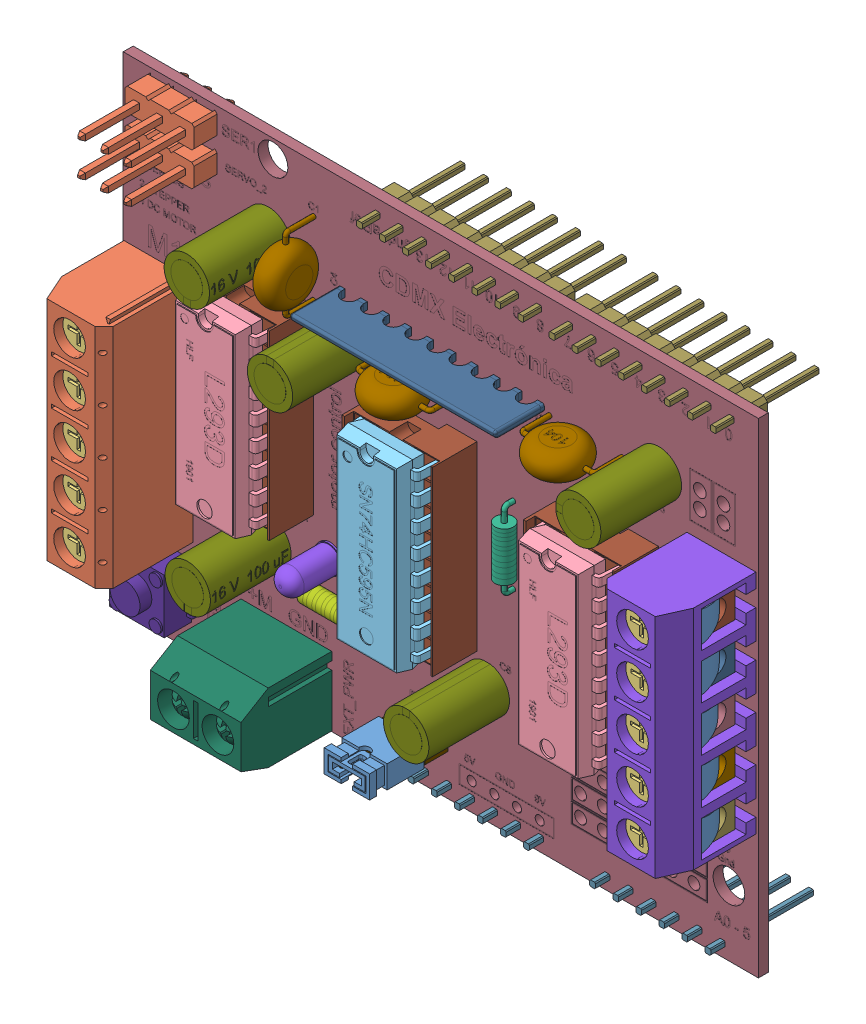
SolidWorks assembly shield-l293d, configuration Default. Lengths in mm.
Overall size (70 53.4 19.79).
64 component instances, 31 part files, 0 mates.
Components (placement in the parent):
- shield-l293d.step-1: shield-l293d.step [Default] at origin size (70 53.4 19.79)
  - bornera 5 pines.step-1: bornera 5 pines.step [Default] at (-31.0088 -3.6709 1.2) x (0 -1 0) z (0 0 1) size (25.5 7.6 12)
    - parte de la bornera_modulo_shield.step-1: parte de la bornera_modulo_shield.step [Default] at (-10 -3.5 5) size (3.8 1.71 4.12)
    - parte de la bornera_modulo_shield.step-2: parte de la bornera_modulo_shield.step [Default] at (-5.0316 -3.4204 4.9792) size (3.8 1.71 4.12)
    - parte de la bornera_modulo_shield.step-3: parte de la bornera_modulo_shield.step [Default] at (-0.05 -3.4087 5.0853) size (3.8 1.71 4.12)
    - parte de la bornera_modulo_shield.step-4: parte de la bornera_modulo_shield.step [Default] at (5.1 -3.4627 4.9734) size (3.8 1.71 4.12)
    - parte de la bornera_modulo_shield.step-5: parte de la bornera_modulo_shield.step [Default] at (10 -3.5442 5.0595) size (3.8 1.71 4.12)
    - bornera 5 pines-0.step-1: bornera 5 pines-0.step [Default] at origin size (25.5 7.6 9.8)
    - bornera 5 pines-1.step-1: bornera 5 pines-1.step [Default] at origin size (3.8 6 8)
    - bornera 5 pines-2.step-1: bornera 5 pines-2.step [Default] at origin size (3.8 6 8)
    - bornera 5 pines-3.step-1: bornera 5 pines-3.step [Default] at origin size (3.8 6 8)
    - bornera 5 pines-4.step-1: bornera 5 pines-4.step [Default] at origin size (3.8 6 8)
    - bornera 5 pines-5.step-1: bornera 5 pines-5.step [Default] at origin size (3.8 6 8)
  - bornera 5 pines_1.step-1: bornera 5 pines_1.step [Default] at (31.0291 -0.4912 1.2) x (0 1 0) z (0 0 1) size (25.5 7.6 12)
    - parte de la bornera_modulo_shield.step-1: parte de la bornera_modulo_shield.step [Default] at (-10 -3.5 5) size (3.8 1.71 4.12)
    - parte de la bornera_modulo_shield.step-2: parte de la bornera_modulo_shield.step [Default] at (-5.0316 -3.4204 4.9792) size (3.8 1.71 4.12)
    - parte de la bornera_modulo_shield.step-3: parte de la bornera_modulo_shield.step [Default] at (-0.05 -3.4087 5.0853) size (3.8 1.71 4.12)
    - parte de la bornera_modulo_shield.step-4: parte de la bornera_modulo_shield.step [Default] at (5.1 -3.4627 4.9734) size (3.8 1.71 4.12)
    - parte de la bornera_modulo_shield.step-5: parte de la bornera_modulo_shield.step [Default] at (10 -3.5442 5.0595) size (3.8 1.71 4.12)
    - bornera 5 pines_1-6.step-1: bornera 5 pines_1-6.step [Default] at origin size (25.5 7.6 9.8)
    - bornera 5 pines_1-7.step-1: bornera 5 pines_1-7.step [Default] at origin size (3.8 6 8)
    - bornera 5 pines_1-8.step-1: bornera 5 pines_1-8.step [Default] at origin size (3.8 6 8)
    - bornera 5 pines_1-9.step-1: bornera 5 pines_1-9.step [Default] at origin size (3.8 6 8)
    - bornera 5 pines_1-10.step-1: bornera 5 pines_1-10.step [Default] at origin size (3.8 6 8)
    - bornera 5 pines_1-11.step-1: bornera 5 pines_1-11.step [Default] at origin size (3.8 6 8)
  - header_macho_6pines.step-1: header_macho_6pines.step [Default] at (31 -25.33 -0.33) x (0 1 0) z (-1 0 0) size (2.54 11.34 15.24)
  - header_macho_6pines.step-2: header_macho_6pines.step [Default] at (11 -25.33 -0.33) x (0 1 0) z (-1 0 0) size (2.54 11.34 15.24)
  - bornera.step-1: bornera.step [Default] at (-17 -22.8156 1.1155) x (1 0 0) z (0 -1 0) size (10.5 13.75 7.6)
  - capacitor 16 v 100uf.step-1: capacitor 16 v 100uf.step [Default] at (-19 -12 1) size (5.01 4.97 12)
  - capacitor 16 v 100uf.step-2: capacitor 16 v 100uf.step [Default] at (-19 17.4 1.1) size (5.01 4.97 12)
  - capacitor 16 v 100uf.step-3: capacitor 16 v 100uf.step [Default] at (5.0692 -13.9959 1) x (-1 0 0) z (0 0 1) size (5.01 4.97 12)
  - capacitor 16 v 100uf.step-4: capacitor 16 v 100uf.step [Default] at (24.0326 16.0366 1) x (0 -1 0) z (0 0 1) size (5.01 4.97 12)
  - Boton_pulsador.step-1: Boton_pulsador.step [Default] at (-30.5 -21 1.1) x (0 1 0) z (0 0 1) size (6 7.3 5.7)
  - 2x1, Male, Header, 0.1in pitch_modulo_shield.step-1: 2x1, Male, Header, 0.1in pitch_modulo_shield.step [Default] at (-3 -21.2824 2.2824) x (1 0 0) z (0 -1 0) size (5.08 11.18 2.54)
  - Pin header jumper_modulo_shield.step-1: Pin header jumper_modulo_shield.step [Default] at (-0.5 -21.3 3.7) x (-1 0 0) z (0 0 1) size (5 2.5 6)
  - header_3_pines.step-1: header_3_pines.step [Default] at (-25.92 24.9074 1.0926) x (-1 0 0) z (0 1 0) size (7.62 11.94 2.54)
  - header_3_pines.step-2: header_3_pines.step [Default] at (-31 21.2074 1.1026) x (1 0 0) z (0 -1 0) size (7.62 11.94 2.54)
  - capacitor 16 v 100uf.step-5: capacitor 16 v 100uf.step [Default] at (-9.9308 12.0041 1) x (-1 0 0) z (0 0 1) size (5.01 4.97 12)
  - pija_bornera_modulo_shield.step-1: pija_bornera_modulo_shield.step [Default] at (-31 6.3 10) size (3.5 3.5 3.53)
  - pija_bornera_modulo_shield.step-2: pija_bornera_modulo_shield.step [Default] at (-31 1.3 10) size (3.5 3.5 3.53)
  - pija_bornera_modulo_shield.step-3: pija_bornera_modulo_shield.step [Default] at (-31 -3.7 10) size (3.5 3.5 3.53)
  - pija_bornera_modulo_shield.step-4: pija_bornera_modulo_shield.step [Default] at (-31 -8.7 10) size (3.5 3.5 3.53)
  - pija_bornera_modulo_shield.step-5: pija_bornera_modulo_shield.step [Default] at (-31 -13.7 10) size (3.5 3.5 3.53)
  - pija_bornera_modulo_shield.step-6: pija_bornera_modulo_shield.step [Default] at (31.02 9.5 10) size (3.5 3.5 3.53)
  - pija_bornera_modulo_shield.step-7: pija_bornera_modulo_shield.step [Default] at (31.04 4.5 10) size (3.5 3.5 3.53)
  - pija_bornera_modulo_shield.step-8: pija_bornera_modulo_shield.step [Default] at (31.02 -0.5 10) size (3.5 3.5 3.53)
  - pija_bornera_modulo_shield.step-9: pija_bornera_modulo_shield.step [Default] at (31.02 -5.5 10) size (3.5 3.5 3.53)
  - pija_bornera_modulo_shield.step-10: pija_bornera_modulo_shield.step [Default] at (31 -10.5 10) size (3.5 3.5 3.53)
  - L293D v1.step-1: L293D v1.step [Default] at (-18.8122 3.2596 6.7281) x (0 -1 0) z (-1 0 0) size (20 7.1 9.4)
  - L293D v1.step-2: L293D v1.step [Default] at (18.9878 -0.7404 6.7281) x (0 -1 0) z (-1 0 0) size (20 7.1 9.4)
  - sn74hc595.step-1: sn74hc595.step [Default] at (-1.0256 -0.6596 6.734) x (0 -1 0) z (-1 0 0) size (20 7.1 9.2)
  - resistencia_1.step-1: resistencia_1.step [Default] at (8 -1.5493 2.1077) x (1 0 0) z (0 1 0) size (2 3.5 8.9)
  - resistencia_2.step-1: resistencia_2.step [Default] at (-8.2215 -13.7708 2.1077) x (0 1 0) z (-1 0 0) size (2 3.5 9.1)
  - led_verde.step-1: led_verde.step [Default] at (-12 -10 1.3) size (3 3 7.5)
  - capacitor_v2.step-1: capacitor_v2.step [Default] at (-15.4978 17.4982 4.1999) x (0 -1 0) z (0 0 1) size (8.5 3 8)
  - capacitor_v2.step-2: capacitor_v2.step [Default] at (-1.9996 13.996 4.3) x (-1 0 0) z (0 0 1) size (8.5 3 8)
  - capacitor_v2.step-3: capacitor_v2.step [Default] at (16.0004 16.996 4.2) x (-1 0 0) z (0 0 1) size (8.5 3 8)
  - resistencia_matriz.step-1: resistencia_matriz.step [Default] at (0 16 1.5) size (22.68 0.8 6.5)
  - base_16_pines.step-1: base_16_pines.step [Default] at (-19.0059 2.9889 1) x (0 -1 0) z (0 0 1) size (20 10 7)
  - base_16_pines.step-2: base_16_pines.step [Default] at (-1.0059 -1.0111 1) x (0 -1 0) z (0 0 1) size (20 10 7)
  - base_16_pines.step-3: base_16_pines.step [Default] at (18.9941 -1.0111 1) x (0 -1 0) z (0 0 1) size (20 10 7)
  - header_8.step-1: header_8.step [Default] at (-7 25.17 0.07) x (0 -1 0) z (1 0 0) size (2.54 11.34 20.32)
  - header_8.step-2: header_8.step [Default] at (32 25.17 0.07) x (0 1 0) z (-1 0 0) size (2.54 11.34 20.32)
  - shield escudo.step-1: shield escudo.step [Default] at origin size (70 53.4 1.15)
